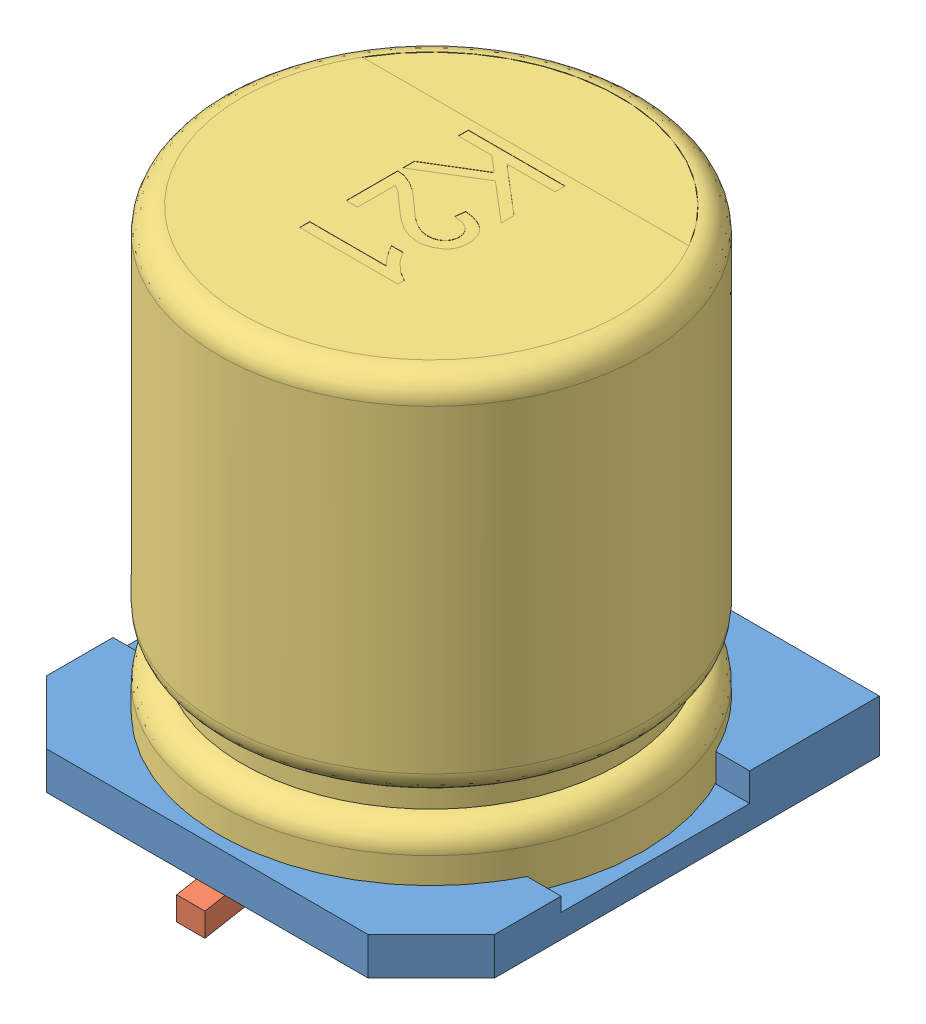
SolidWorks assembly SMD-CAP-ALU-K21, configuration Default. Lengths in mm.
Overall size (19 21.5 20.4).
4 component instances, 3 part files, 9 mates.
Components (placement in the parent):
- Foot-1: Foot [Default] at origin size (19 3.5 19)
- P-1: P [Default] at (0 1 10.2) x (0 -1 0) z (0 0 1) size (2 1.2 5.5)
- P-2: P [Default] at (0 1 -10.2) x (0 -1 0) z (0 0 -1) size (2 1.2 5.5)
- CAN-1: CAN [Default] at (0 2.3 0) x (0 0 1) z (-1 0 0) size (18 19.2 18)
Mates (geometry in assembly coordinates):
- Distance1: distance = 0 mm: plane of assembly through (0 0 0) normal (0 1 0); plane of assembly; plane of Foot-1 through (0 0 0) normal (0 -1 0)
- Coincident2: coincident aligned: plane of Foot-1 through (0 0 0) normal (0 0 1); plane of assembly through (0 0 0) normal (0 0 1)
- Coincident3: coincident aligned: plane of Foot-1 through (0 0 0) normal (1 0 0); plane of assembly through (0 0 0) normal (1 0 0)
- Coincident5: coincident aligned: plane of P-1 through (0 1 10.2) normal (1 0 0); plane of assembly through (0 0 0) normal (1 0 0)
- Distance3: distance = 0.7 mm aligned: plane of P-1 through (0.6 1 10.2) normal (0 0 1); plane of Foot-1 through (-9.5 3.5 9.5) normal (0 0 1)
- Coincident8: coincident: line of P-1 through (0.6 0 10.2) axis (-1 0 0); plane of assembly through (0 0 0) normal (0 1 0)
- Coincident12: coincident anti-aligned: plane of CAN-1 through (0 2.3 0) normal (-1 0 0); plane of assembly through (0 0 0) normal (1 0 0)
- Coincident13: coincident aligned: plane of CAN-1 through (0 2.3 0) normal (0 0 1); plane of assembly through (0 0 0) normal (0 0 1)
- Coincident14: coincident anti-aligned: plane of Foot-1 through (0 2.3 0) normal (0 1 0); plane of CAN-1 through (0 2.3 0) normal (0 -1 0)
